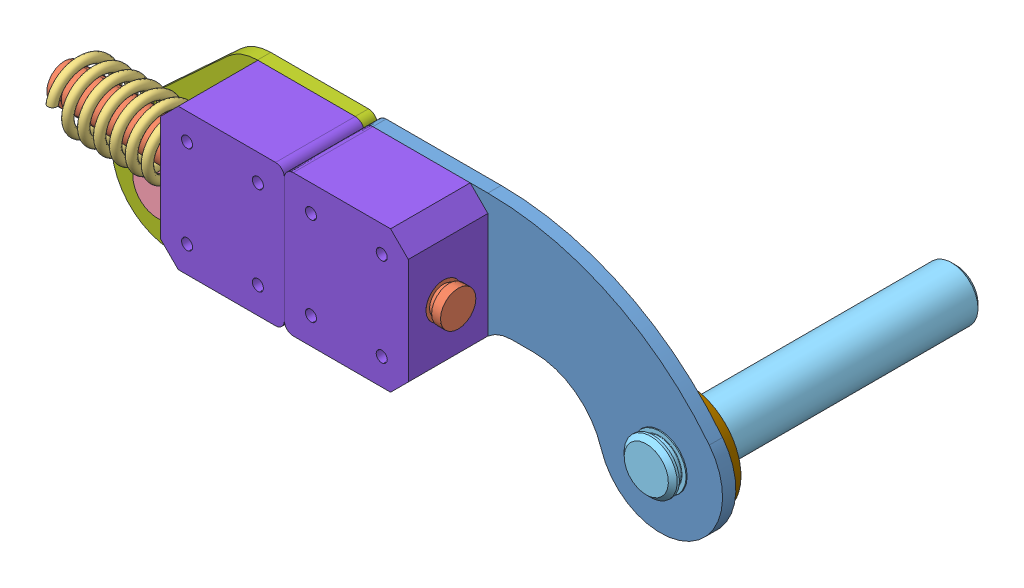
SolidWorks assembly Assem1-knee-mod2-front, configuration Défaut. Lengths in mm.
Overall size (71.85 24.93 44.48).
15 component instances, 9 part files, 30 mates.
Components (placement in the parent):
- Part2-knee-mod3-front-1: Part2-knee-mod3-front [Défaut] at (3.122 0.7472 0) size (40.53 23.53 1.5)
- part2-knee-mod1-1: part2-knee-mod1 [Default] at (-59.238 9.2472 5.75) x (0 0.704418 -0.709786) z (0 -0.709786 -0.704418) size (4 44.5 4)
- Spring_DF-1670-2: Spring_DF-1670 [Défaut] at (-46.4518 9.2472 5.75) x (0 0.749041 0.662524) z (-1 0 0) size (8.62 8.62 12.7)
- al_d6_1-1: al_d6_1 [Default] at (-51.878 0.7472 2.59) x (-0.923728 -0.383049 0) z (0.383049 -0.923728 0) size (6 13 6)
- d5l35-2: d5l35 [Default] at (3.122 0.7472 -32.65) x (0.954097 0.299497 0) z (0.299497 -0.954097 0) size (6 35 6)
- lock washer for shafts_din-3: lock washer for shafts_din [PreviewCfg] at (-57.598 9.2472 5.75) x (0 -0.355992 -0.934489) z (1 0 0) size (2.25 1.94 0.2)
- lock washer for shafts_din-4: lock washer for shafts_din [PreviewCfg] at (-16.378 9.2472 5.75) x (0 -1 0) z (-1 0 0) size (2.25 1.94 0.2)
- lock washer for shafts_din-5: lock washer for shafts_din [PreviewCfg] at (-51.878 0.7472 0.65) x (0.923728 0.383049 0) z (0 0 -1) size (2.25 1.94 0.2)
- lock washer for shafts_din-6: lock washer for shafts_din [PreviewCfg] at (3.122 0.7472 1.05) size (2.25 1.94 0.2)
- Part1-knee-mod3-front-1: Part1-knee-mod3-front [Défaut] at (-51.878 0.7472 0) x (-1 0 0) z (0 0 -1) size (28.52 23.53 1.5)
- part4-knee-mod1-1: part4-knee-mod1 [Défaut] at (-37.378 9.2472 5.75) x (0 1 0) z (-1 0 0) size (16 9 14)
- part4-knee-mod1-2: part4-knee-mod1 [Défaut] at (-23.378 9.2472 5.75) x (0 -1 0) z (1 0 0) size (16 9 14)
- Washer-d6p5-12-1: Washer-d6p5-12 [Défaut] at (3.122 0.7472 -1.55) x (-0.619481 -0.785012 0) z (0 0 1) size (12 12 1.6)
- Washer-d6p5-12-2: Washer-d6p5-12 [Défaut] at (-51.878 0.7472 -1.55) x (-0.619481 -0.785012 0) z (0 0 1) size (12 12 1.6)
- lock washer for shafts_din-7: lock washer for shafts_din [PreviewCfg] at (-51.878 0.7472 -8.67) x (0.923728 0.383049 0) z (0 0 -1) size (2.25 1.94 0.2)
Mates (geometry in assembly coordinates):
- Coaxiale19: concentric aligned: cylinder of part2-knee-mod1-1 through (-59.238 9.2472 5.75) axis (-1 0 0) radius 2; line of Spring_DF-1670-2 through (-46.4518 9.2472 5.75) axis (-1 0 0)
- Coaxiale21: concentric aligned: cylinder of Part2-knee-mod3-front-1 through (3.122 0.7472 0.75) axis (0 0 -1) radius 3.025; cylinder of d5l35-2 through (3.122 0.7472 -32.65) axis (0 0 -1) radius 3
- Coïncidente21: coincident aligned: plane of al_d6_1-1 through (-56.6209 4.9501 0.85) normal (0 0 1); plane of d5l35-2 through (2.0438 4.1819 0.85) normal (0 0 1)
- Coïncidente29: coincident anti-aligned: plane of part2-knee-mod1-1 through (-57.598 10.3743 4.6143) normal (-1 0 0); plane of lock washer for shafts_din-3 through (-57.598 9.2472 5.75) normal (1 0 0)
- Coaxiale31: concentric aligned: cylinder of part2-knee-mod1-1 through (-14.738 9.2472 5.75) axis (1 0 0) radius 1.6; cylinder of lock washer for shafts_din-3 through (-57.798 9.2472 5.75) axis (1 0 0) radius 0.4
- Coaxiale35: concentric anti-aligned: cylinder of part2-knee-mod1-1 through (-14.738 9.2472 5.75) axis (1 0 0) radius 1.6; cylinder of lock washer for shafts_din-4 through (-16.178 9.2472 5.75) axis (-1 0 0) radius 0.4
- Coïncidente30: coincident anti-aligned: plane of part2-knee-mod1-1 through (-16.378 10.7792 4.2063) normal (1 0 0); plane of lock washer for shafts_din-4 through (-16.378 9.2472 5.75) normal (-1 0 0)
- Coaxiale36: concentric anti-aligned: cylinder of al_d6_1-1 through (-54.878 0.7472 -47.4388) axis (0 0 1) radius 2.5; cylinder of ? through (-54.878 0.7472 0.85) axis (0 0 -1) radius 0.4
- Coïncidente31: coincident aligned: plane of al_d6_1-1 through (-56.6209 4.9501 0.85) normal (0 0 1); plane of ? through (-54.878 0.7472 0.85) normal (0 0 1)
- Coaxiale37: concentric anti-aligned: cylinder of d5l35-2 through (3.122 0.7472 17.35) axis (0 0 -1) radius 2.5; cylinder of lock washer for shafts_din-6 through (3.122 0.7472 0.85) axis (0 0 1) radius 0.4
- Coïncidente32: coincident anti-aligned: plane of d5l35-2 through (2.0438 4.1819 0.85) normal (0 0 1); plane of lock washer for shafts_din-6 through (3.122 0.7472 0.85) normal (0 0 -1)
- Coïncidente38: coincident aligned: plane of Part2-knee-mod3-front-1 through (3.122 0.7472 -0.75) normal (0 0 -1); plane of Part1-knee-mod3-front-1 through (-54.878 0.7472 -0.75) normal (0 0 -1)
- Coïncidente39: coincident aligned: plane of Part2-knee-mod3-front-1 through (-30.378 17.2472 0.75) normal (0 1 0); plane of Part1-knee-mod3-front-1 through (-33.378 17.2472 -0.75) normal (0 1 0)
- Coaxiale49: concentric aligned: cylinder of al_d6_1-1 through (-54.878 0.7472 2.59) axis (0 0 1) radius 3; cylinder of Part1-knee-mod3-front-1 through (-54.878 0.7472 -0.75) axis (0 0 1) radius 3.025
- Distance10: distance = 0.1 mm aligned: plane of al_d6_1-1 through (-53.6209 4.9501 0.85) normal (0 0 1); plane of Part1-knee-mod3-front-1 through (-51.878 0.7472 0.75) normal (0 0 1)
- Coïncidente40: coincident anti-aligned: plane of Part1-knee-mod3-front-1 through (-54.878 0.7472 0.75) normal (0 0 1); plane of part4-knee-mod1-1 through (-47.378 1.2472 0.75) normal (0 0 -1)
- Coaxiale52: concentric anti-aligned: cylinder of Part1-knee-mod3-front-1 through (-36.378 14.2472 -0.75) axis (0 0 1) radius 0.85; cylinder of part4-knee-mod1-1 through (-36.378 14.2472 0.75) axis (0 0 -1) radius 0.625
- Coaxiale53: concentric anti-aligned: cylinder of Part1-knee-mod3-front-1 through (-44.378 4.2472 -0.75) axis (0 0 1) radius 0.85; cylinder of part4-knee-mod1-1 through (-44.378 4.2472 0.75) axis (0 0 -1) radius 0.625
- Coïncidente41: coincident anti-aligned: plane of Part2-knee-mod3-front-1 through (3.122 0.7472 0.75) normal (0 0 1); plane of part4-knee-mod1-2 through (-16.378 17.2472 0.75) normal (0 0 -1)
- Coaxiale54: concentric aligned: cylinder of Part2-knee-mod3-front-1 through (-19.378 14.2472 0.75) axis (0 0 -1) radius 0.85; cylinder of part4-knee-mod1-2 through (-19.378 14.2472 0.75) axis (0 0 -1) radius 0.625
- Coaxiale55: concentric aligned: cylinder of Part2-knee-mod3-front-1 through (-27.378 4.2472 0.75) axis (0 0 -1) radius 0.85; cylinder of part4-knee-mod1-2 through (-27.378 4.2472 0.75) axis (0 0 -1) radius 0.625
- Coaxiale56: concentric anti-aligned: cylinder of part2-knee-mod1-1 through (-59.238 9.2472 5.75) axis (-1 0 0) radius 2; cylinder of part4-knee-mod1-1 through (-47.378 9.2472 5.75) axis (1 0 0) radius 2
- Coïncidente42: coincident anti-aligned: plane of lock washer for shafts_din-4 through (-16.378 9.2472 5.75) normal (-1 0 0); plane of part4-knee-mod1-2 through (-16.378 17.2472 9.75) normal (1 0 0)
- Concentric158: concentric aligned: cylinder of d5l35-2 through (3.122 0.7472 -32.65) axis (0 0 -1) radius 3; cylinder of Washer-d6p5-12-1 through (3.122 0.7472 -0.75) axis (0 0 -1) radius 3.25
- Coincident166: coincident anti-aligned: plane of Part2-knee-mod3-front-1 through (3.122 0.7472 -0.75) normal (0 0 -1); plane of Washer-d6p5-12-1 through (3.122 0.7472 -0.75) normal (0 0 1)
- Concentric159: concentric anti-aligned: cylinder of al_d6_1-1 through (-54.878 0.7472 2.59) axis (0 0 1) radius 3; cylinder of Washer-d6p5-12-2 through (-54.878 0.7472 -0.75) axis (0 0 -1) radius 3.25
- Coincident167: coincident anti-aligned: plane of Part1-knee-mod3-front-1 through (-54.878 0.7472 -0.75) normal (0 0 -1); plane of Washer-d6p5-12-2 through (-54.878 0.7472 -0.75) normal (0 0 1)
- Coïncidente44: coincident aligned: plane of al_d6_1-1 through (-55.8356 3.0565 -8.67) normal (0 0 -1); plane of ? through (-54.878 0.7472 -8.67) normal (0 0 -1)
- Coaxiale58: concentric anti-aligned: cylinder of al_d6_1-1 through (-54.878 0.7472 -47.4388) axis (0 0 1) radius 2.5; cylinder of ? through (-54.878 0.7472 -8.47) axis (0 0 -1) radius 0.4
- Distance11: distance = 0 mm anti-aligned: plane of part4-knee-mod1-2 through (-30.378 17.2472 9.75) normal (-1 0 0); plane of part4-knee-mod1-1 through (-30.378 1.2472 9.75) normal (1 0 0)
